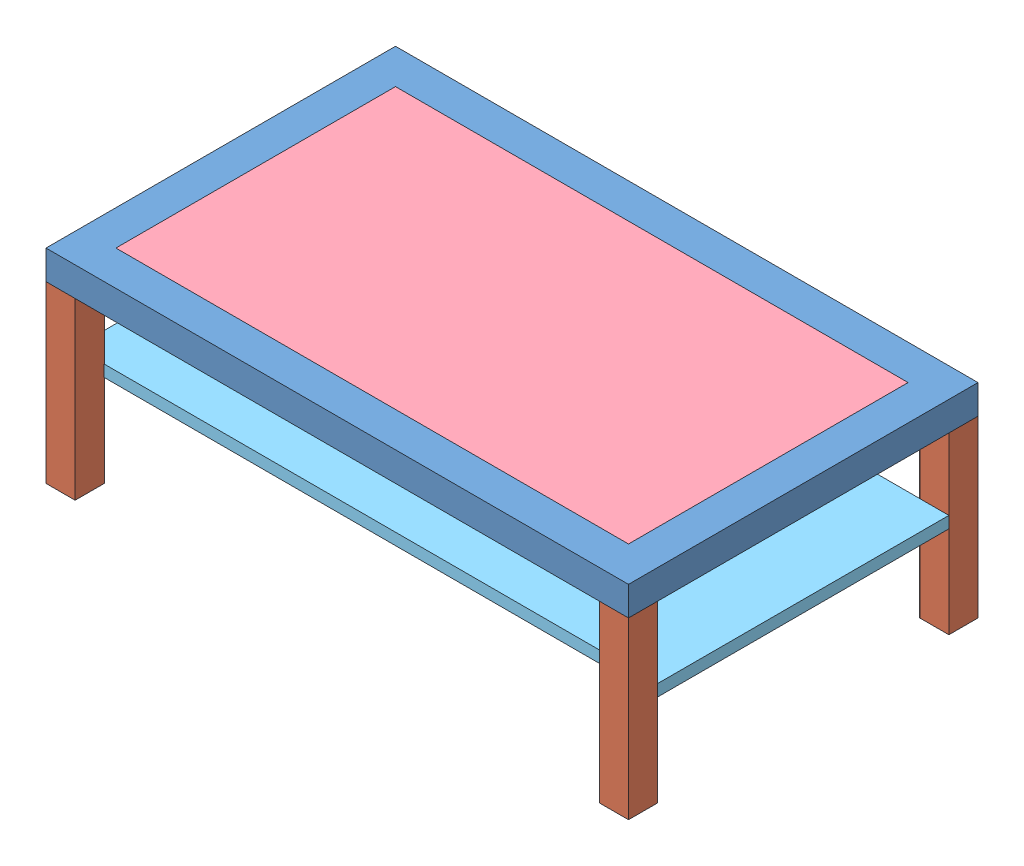
SolidWorks assembly Ch 11_Table Assembly, configuration Default. Lengths in mm.
Overall size (1000 352 600).
15 component instances, 6 part files, 22 mates.
Components (placement in the parent):
- Table Top-1: Table Top [Default] at origin size (1000 50 600)
- Leg-1: Leg [Default] x (-1 0 0) z (0 -1 0) size (50 50 300)
- Pin-1: Pin [Default] at (0 0 265) x (-1 0 0) z (0 0 -1) size (15 15 30)
- Glass Top-1: Glass Top [Default] at (0 40 0) x (1 0 0) z (0 1 0) size (880 480 10)
- Leg-2: Leg [Default] at (0 -300 0) x (1 0 0) z (0 1 0) size (50 50 300)
- Pin-2: Pin [Default] at (0 0 235) size (15 15 30)
- Pin-3: Pin [Default] at (0 0 -235) x (-1 0 0) z (0 0 -1) size (15 15 30)
- Leg-3: Leg [Default] at (0 -300 0) x (-1 0 0) z (0 1 0) size (50 50 300)
- Leg-4: Leg [Default] x (1 0 0) z (0 -1 0) size (50 50 300)
- Pin-4: Pin [Default] at (0 0 -265) size (15 15 30)
- Mid surface-1: Mid surface [Default] at (0 -142.5 0) x (1 0 0) z (0 1 0) size (1000 500 20)
- Floor pad-1: Floor pad [Default] at (0 -300 0) x (-1 0 0) z (0 -1 0) size (30 30 2)
- Floor pad-2: Floor pad [Default] at (0 -302 0) x (1 0 0) z (0 1 0) size (30 30 2)
- Floor pad-3: Floor pad [Default] at (0 -302 0) x (-1 0 0) z (0 1 0) size (30 30 2)
- Floor pad-4: Floor pad [Default] at (0 -300 0) x (1 0 0) z (0 -1 0) size (30 30 2)
Mates (geometry in assembly coordinates):
- InPlace1: in place: plane of Table Top-1 through (0 0 0) normal (0 -1 0); plane of Leg-1 through (0 0 0) normal (0 -1 0); moOrthogonalPlaneRef_w of Table Top-1 through (0 0 0) normal (0 -1 0); unknown of Leg-1; plane of Table Top-1 through (0 0 0) normal (0 -1 0); line of Leg-1 through (55 -55 0) axis (0 0 -1); plane of Table Top-1 through (0 0 0) normal (0 -1 0); unknown of Leg-1
- Coincident1: coincident aligned: plane of Table Top-1; plane of Leg-1
- Coincident2: coincident aligned: moOrthogonalPlaneRef_w of Table Top-1 through (0 0 0) normal (0 0 -1); plane of Leg-1
- Coincident3: coincident anti-aligned: moOrthogonalPlaneRef_w of Table Top-1 through (0 0 0) normal (1 0 0); plane of Leg-1
- InPlace3: in place: plane of Leg-1 through (-475 -150 265) normal (0 0 -1); plane of Pin-1 through (0 0 265) normal (0 0 -1); plane of Leg-1 through (-475 -150 265) normal (0 0 -1); unknown of Pin-1; plane of Leg-1 through (-475 -150 265) normal (0 0 -1); plane of Pin-1 through (0 0 265) normal (-1 0 0); plane of Leg-1 through (-475 -150 265) normal (0 0 -1); unknown of Pin-1
- Coincident7: coincident aligned: plane of Leg-1; plane of Pin-1
- Coincident8: coincident aligned: moOrthogonalPlaneRef_w of Leg-1 through (0 0 265) normal (0 1 0); plane of Pin-1
- Coincident9: coincident anti-aligned: moOrthogonalPlaneRef_w of Leg-1 through (0 0 265) normal (1 0 0); plane of Pin-1 through (0 0 265) normal (-1 0 0)
- InPlace4: in place: plane of Table Top-1 through (0 40 0) normal (0 1 0); plane of Glass Top-1 through (0 40 0) normal (0 1 0); plane of Table Top-1 through (0 40 0) normal (0 1 0); plane of Glass Top-1 through (0 40 0) normal (0 0 -1); plane of Table Top-1 through (0 40 0) normal (0 1 0); line of Glass Top-1 through (-55 0 40) axis (0 1 0); plane of Table Top-1 through (0 40 0) normal (0 1 0); unknown of Glass Top-1
- Coincident10: coincident aligned: plane of Table Top-1; plane of Glass Top-1
- Coincident11: coincident aligned: moOrthogonalPlaneRef_w of Table Top-1 through (0 40 0) normal (0 0 -1); plane of Glass Top-1 through (0 40 0) normal (0 0 -1)
- Coincident12: coincident anti-aligned: moOrthogonalPlaneRef_w of Table Top-1 through (0 40 0) normal (-1 0 0); plane of Glass Top-1
- InPlace5: in place: plane of Mid surface-1 through (0 -142.5 0) normal (0 1 0); plane of Mid surface-1 through (0 -142.5 0) normal (0 0 -1); line of Mid surface-1 through (-55 0 -142.5) axis (0 1 0); unknown of Mid surface-1
- Coincident13: coincident aligned: plane of Mid surface-1; plane of assembly
- Coincident14: coincident aligned: plane of Mid surface-1 through (0 -142.5 0) normal (0 0 -1); moOrthogonalPlaneRef_w of assembly
- Coincident15: coincident anti-aligned: plane of Mid surface-1; moOrthogonalPlaneRef_w of assembly
- Coincident16: coincident aligned: plane of Leg-1 through (-500 -300 300) normal (-1 0 0); plane of Mid surface-1 through (-500 -122.5 -250) normal (-1 0 0)
- Coincident17: coincident anti-aligned: plane of Leg-3 through (-500 0 -250) normal (0 0 1); plane of Mid surface-1 through (-500 -122.5 -250) normal (0 0 -1)
- InPlace6: in place: plane of Leg-1 through (0 -300 0) normal (0 -1 0); plane of Floor pad-1 through (0 -300 0) normal (0 -1 0); plane of Leg-1 through (0 -300 0) normal (0 -1 0); unknown of Floor pad-1; plane of Leg-1 through (0 -300 0) normal (0 -1 0); line of Floor pad-1 through (-55 0 -300) axis (0 -1 0); plane of Leg-1 through (0 -300 0) normal (0 -1 0); unknown of Floor pad-1
- Coincident18: coincident aligned: plane of Leg-1; plane of Floor pad-1
- Coincident19: coincident aligned: moOrthogonalPlaneRef_w of Leg-1 through (0 -300 0) normal (0 0 -1); plane of Floor pad-1
- Coincident20: coincident anti-aligned: moOrthogonalPlaneRef_w of Leg-1 through (0 -300 0) normal (1 0 0); plane of Floor pad-1
